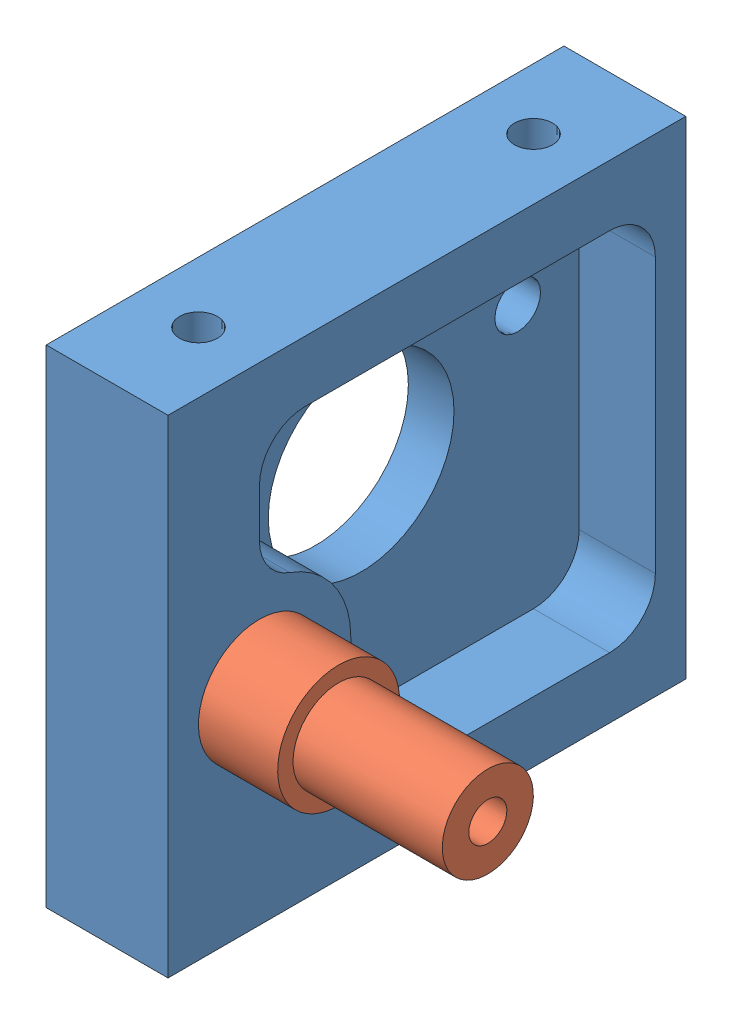
SolidWorks assembly Assem1, configuration Default. Lengths in mm.
Overall size (23 32 34).
2 component instances, 2 part files, 2 mates.
Components (placement in the parent):
- motor_mount_left-1: motor_mount_left [Default] at (-36.1392 -13.1466 32.0208) size (8 32 34)
- wheel_rod-1: wheel_rod [Default] at (-13.1392 0.2534 26.0208) x (-1 0 0) z (0 -0.69651 -0.717547) size (23 8 8)
Mates (geometry in assembly coordinates):
- Concentric1: concentric anti-aligned: cylinder of motor_mount_left-1 through (-36.1402 0.2534 26.0208) axis (1 0 0) radius 3; circle of wheel_rod-1
- Coincident1: coincident anti-aligned: plane of motor_mount_left-1 through (-28.1392 -13.1466 32.0208) normal (1 0 0); plane of wheel_rod-1 through (-28.1392 2.406 23.9313) normal (-1 0 0)
